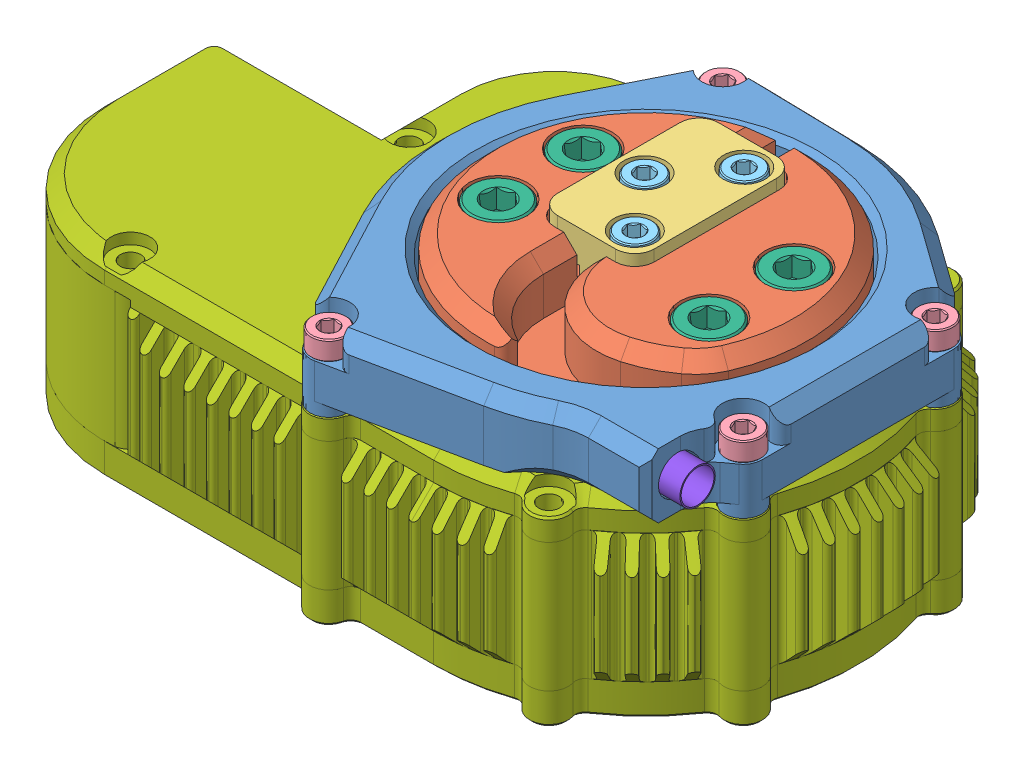
SolidWorks assembly HEBI Gripper Spool, configuration Default. Lengths in mm.
Overall size (109.71 43.69 73.67).
16 component instances, 8 part files, 3 mates.
Components (placement in the parent):
- HEBI Robotics-Default (X5-9)_PM-2293-01-1: HEBI Robotics-Default (X5-9)_PM-2293-01 [Default] x (-1 0 0) z (0 0 -1) size (65.4 11.85 69.3)
- HEBI Robotics-Default (X5-9)_PM-2292-01-1: HEBI Robotics-Default (X5-9)_PM-2292-01 [Default] at (0.0007 -3.95 0.0008) x (-1 0 0) z (0 0 -1) size (50 11 50)
- HEBI Robotics-Default (X5-9)_PM-2290-01-1: HEBI Robotics-Default (X5-9)_PM-2290-01 [Default] at (-3.2493 3.55 -6.4992) x (-1 0 0) z (0 0 -1) size (15 7 25)
- HEBI Robotics-Default (X5-9)_PP-2205-35-1: HEBI Robotics-Default (X5-9)_PP-2205-35 [Default] at (-18.09 -34.551 -30) x (0.92376 0 -0.382972) z (0 -1 0) size (5.5 5.5 38.26)
- HEBI Robotics-Default (X5-9)_PP-2205-35-2: HEBI Robotics-Default (X5-9)_PP-2205-35 [Default] at (30 -34.551 14.91) x (0.92376 0 -0.382972) z (0 -1 0) size (5.5 5.5 38.26)
- HEBI Robotics-Default (X5-9)_PP-2205-35-3: HEBI Robotics-Default (X5-9)_PP-2205-35 [Default] at (-15.79 -34.551 33.5) x (0.92376 0 -0.382972) z (0 -1 0) size (5.5 5.5 38.26)
- HEBI Robotics-Default (X5-9)_PP-2205-35-4: HEBI Robotics-Default (X5-9)_PP-2205-35 [Default] at (30 -34.551 -14.91) x (0.92376 0 -0.382972) z (0 -1 0) size (5.5 5.5 38.26)
- HEBI Robotics-Default (X5-9)_PP-2205-08-1: HEBI Robotics-Default (X5-9)_PP-2205-08 [Default] at (-6.7493 -2.45 -6.4992) x (0.940312 0 -0.340315) z (0 -1 0) size (5.5 5.5 11.2)
- HEBI Robotics-Default (X5-9)_PP-2205-08-2: HEBI Robotics-Default (X5-9)_PP-2205-08 [Default] at (0.2507 -2.45 -14.9992) x (0.940312 0 -0.340315) z (0 -1 0) size (5.5 5.5 11.2)
- HEBI Robotics-Default (X5-9)_PP-2205-08-3: HEBI Robotics-Default (X5-9)_PP-2205-08 [Default] at (0.2507 -2.45 2.0008) x (0.940312 0 -0.340315) z (0 -1 0) size (5.5 5.5 11.2)
- HEBI Robotics-Default (X5-9)_PP-2131-12(PP-2131-12)-1: HEBI Robotics-Default (X5-9)_PP-2131-12(PP-2131-12) [Default] at (16.2542 -9.95 6.4871) x (-0.985138 0 -0.171764) z (0 -1 0) size (8.5 8.5 17.42)
- HEBI Robotics-Default (X5-9)_PP-2131-12(PP-2131-12)-2: HEBI Robotics-Default (X5-9)_PP-2131-12(PP-2131-12) [Default] at (-16.0788 -9.95 6.9072) x (-0.985138 0 -0.171764) z (0 -1 0) size (8.5 8.5 17.42)
- HEBI Robotics-Default (X5-9)_PP-2131-12(PP-2131-12)-3: HEBI Robotics-Default (X5-9)_PP-2131-12(PP-2131-12) [Default] at (16.0802 -9.95 -6.9057) x (-0.985138 0 -0.171764) z (0 -1 0) size (8.5 8.5 17.42)
- HEBI Robotics-Default (X5-9)_PP-2131-12(PP-2131-12)-4: HEBI Robotics-Default (X5-9)_PP-2131-12(PP-2131-12) [Default] at (-16.2529 -9.95 -6.4855) x (-0.985138 0 -0.171764) z (0 -1 0) size (8.5 8.5 17.42)
- HEBI Robotics-Default (X5-9)_X5-Export-1: HEBI Robotics-Default (X5-9)_X5-Export [Default] at (0.0007 -20 0.0008) x (-1 0 -0.000042) z (0 1 0) size (109.71 73.14 31.05)
- HEBI Robotics-Default (X5-9)_PP-2241-01-1: HEBI Robotics-Default (X5-9)_PP-2241-01 [Default] at (20 0 23) x (0 -0.336423 -0.941711) z (0 -0.941711 0.336423) size (5.5 11 5.5)
Mates (geometry in assembly coordinates):
- Lock1: lock: unknown of HEBI Robotics-Default (X5-9)_PM-2293-01-1; unknown of HEBI Robotics-Default (X5-9)_X5-Export-1
- Lock2: lock: unknown of HEBI Robotics-Default (X5-9)_PP-2205-35-3; unknown of HEBI Robotics-Default (X5-9)_X5-Export-1
- Lock3: lock: unknown of HEBI Robotics-Default (X5-9)_PP-2205-35-2; unknown of HEBI Robotics-Default (X5-9)_X5-Export-1
